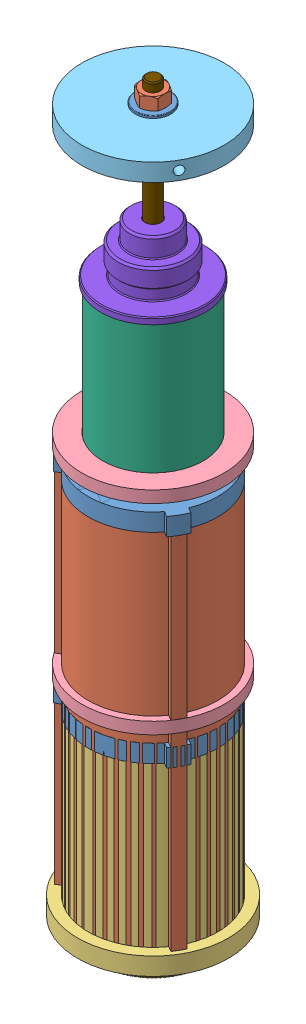
SolidWorks assembly S1B_Motor_Centering_Rings_Test, configuration Default. Lengths in mm.
Overall size (81.28 400.69 81.28).
31 component instances, 21 part files, 12 mates.
Components (placement in the parent):
- S1B_Motor_Casing_Centering_Ring_Jig_Top-1: S1B_Motor_Casing_Centering_Ring_Jig_Top [Default] at origin size (70.46 15.88 73.15) (hidden)
- S1B_Motor_Casing_Centering_Ring_Jig_Bottom-1: S1B_Motor_Casing_Centering_Ring_Jig_Bottom [Default] at (0 -193.675 0) size (69.85 193.68 73.15) (hidden)
- S1B_Propulsion-1: S1B_Propulsion [Default] at (0 -193.675 0) x (1 0 0) z (0 1 0) size (81.28 81.28 400.69)
  - S1B_Thrust_Block-1: S1B_Thrust_Block [Default] at (0 0 -9.525) x (1 0 0) z (0 1 0) size (81.28 9.53 81.28)
  - S1B_Motor_Casing_Centering_Ring-1: S1B_Motor_Casing_Centering_Ring [Default] at (0 0 209.55) x (0 1 0) z (-1 0 0) size (76.71 6.35 76.71)
  - S1B_Motor_Casing_Centering_Ring-2: S1B_Motor_Casing_Centering_Ring [Default] at (0 0 101.6) x (0 1 0) z (-1 0 0) size (76.71 6.35 76.71)
  - S1B_Propulsion_Forward_Bulkhead-1: S1B_Propulsion_Forward_Bulkhead [Default] at (0 0 359.3699) x (1 0 0) z (0 -1 0) size (76.71 9.53 76.71)
  - S1B_Motor_and_Motor_Casing-1: S1B_Motor_and_Motor_Casing [Default] at (-9.4594 -91.7964 22.8199) x (1 0 0) z (0 -1 0) size (79.29 334.89 79.29)
    - S1B_Casing-1: S1B_Casing [Default] at (9.4594 -32.3449 -91.7964) size (54 295.28 54)
    - S1B_Floating_Forward_Closure-1: S1B_Floating_Forward_Closure [Default] at (9.4594 165.0762 -91.7964) x (-0.998129 0 0.061137) z (-0.061137 0 -0.998129) size (50 49.2 50)
    - S1B_Forward_Closure-1: S1B_Forward_Closure [Default] at (9.4594 247.4801 -91.7964) x (0.980788 0 -0.195079) z (0.195079 0 0.980788) size (56.29 45.5 56.29)
    - S1B_Aft_Closure-2: S1B_Aft_Closure [Default] at (-1.9819 -17.8393 -106.5879) x (-0.611829 0 -0.79099) z (-0.79099 0 0.611829) size (56.53 20.87 56.51)
    - S1B_Aerospike_Nozzle-1: S1B_Aerospike_Nozzle [Default] at (9.4594 -15.9281 -91.7964) x (0.109916 0 -0.993941) z (-0.993941 0 -0.109916) size (50 32 50)
    - S1B_Aerospike_Nozzle_Ring-1: S1B_Aerospike_Nozzle_Ring [Default] at (9.4594 -26.9281 -91.7964) x (-0.620514 0 -0.784195) z (0.784195 0 -0.620514) size (44 9 44)
    - S1B_Grains-1: S1B_Grains [Default] at (9.4594 -7.6281 -91.7964) x (0.768519 0 0.639827) z (-0.639827 0 0.768519) size (47 82.35 47)
    - S1B_Grains-2: S1B_Grains [Default] at (9.4594 76.5219 -91.7964) x (-0.910958 0 0.412498) z (-0.412498 0 -0.910958) size (47 82.35 47)
    - S1B_Forward_Seal_Disk-1: S1B_Forward_Seal_Disk [Default] at (9.4594 165.0762 -91.7964) x (-0.490706 0 0.871325) z (0.871325 0 0.490706) size (50.4 6.2 50.4)
    - S1B_Case_Spacer-2: S1B_Case_Spacer [Default] at (9.4594 251.1262 -91.7964) x (0.880165 0 0.474668) z (0.474668 0 -0.880165) size (50.35 79.8 50.35)
    - S1B_9452K118_Oil-Resistant Buna-N O-Ring (031)-2: S1B_9452K118_Oil-Resistant Buna-N O-Ring (031) [9452K118] at (9.4594 75.6219 -91.7964) x (0.952073 0 -0.305872) z (0 -1 0) size (47.73 47.73 1.78)
    - S1B_9452K62_Oil-Resistant Buna-N O-Ring (224)-4: S1B_9452K62_Oil-Resistant Buna-N O-Ring (224) [9452K62] at (9.4594 -20.3449 -91.7964) x (0.99634 0 -0.085477) z (0 1 0) size (51.1 51.1 3.53)
    - S1B_9452K118_Oil-Resistant Buna-N O-Ring (031)-3: S1B_9452K118_Oil-Resistant Buna-N O-Ring (031) [9452K118] at (9.4594 160.3362 -91.7964) x (0.999977 0 -0.006714) z (0 1 0) size (47.73 47.73 1.78)
    - S1B_9452K62_Oil-Resistant Buna-N O-Ring (224)-5: S1B_9452K62_Oil-Resistant Buna-N O-Ring (224) [9452K62] at (9.4594 166.8762 -91.7964) x (0.97725 0 -0.21209) z (0 1 0) size (51.1 51.1 3.53)
    - S1B_9452K118_Oil-Resistant Buna-N O-Ring (031)-4: S1B_9452K118_Oil-Resistant Buna-N O-Ring (031) [9452K118] at (9.4594 -8.5281 -91.7964) x (0.924367 0 -0.381504) z (0 -1 0) size (47.73 47.73 1.78)
    - S1B_Liner-4: S1B_Liner [Default] at (9.4594 -15.9238 -91.7964) x (-0.821303 0 -0.570492) z (0.570492 0 -0.821303) size (50.7 177.66 50.7)
  - S1B_Propulsion_Threaded_Rod_90322A682_High-Strength Steel Threaded Rod-1: S1B_Propulsion_Threaded_Rod_90322A682_High-Strength Steel Threaded Rod [90322A682] at (0 0 330.7949) x (0 -1 0) z (0 0 1) size (7.94 7.94 101.6)
  - S1B_Propulsion_Threaded_Rod_90107A030_316 Stainless Steel Washer-1: S1B_Propulsion_Threaded_Rod_90107A030_316 Stainless Steel Washer [90107A030] at (0 0 369.5299) x (0 1 0) z (0 0 1) size (19.05 19.05 1.27)
  - S1B_Propulsion_Threaded_Rod_90107A030_316 Stainless Steel Washer-2: S1B_Propulsion_Threaded_Rod_90107A030_316 Stainless Steel Washer [90107A030] at (0 0 358.7349) size (19.05 19.05 1.27)
  - S1B_Propulsion_Threaded_Rod_95505A602_Medium-Strength Steel Hex Nut-1: S1B_Propulsion_Threaded_Rod_95505A602_Medium-Strength Steel Hex Nut [95505A602] at (0 0 373.5384) size (12.7 14.66 6.75)
  - S1B_Propulsion_Threaded_Rod_95505A602_Medium-Strength Steel Hex Nut-2: S1B_Propulsion_Threaded_Rod_95505A602_Medium-Strength Steel Hex Nut [95505A602] at (0 0 354.7265) size (12.7 14.66 6.75)
- S1B_Motor_Casing_Centering_Ring_Jig_Bottom_2-2: S1B_Motor_Casing_Centering_Ring_Jig_Bottom_2 [Default] at (0 -193.675 0) size (69.85 85.72 73.15)
- S1B_Motor_Casing_Centering_Ring_Jig_Top-2: S1B_Motor_Casing_Centering_Ring_Jig_Top [Default] at (0 -107.95 0) size (70.46 15.88 73.15)
Mates (geometry in assembly coordinates):
- Concentric1: concentric anti-aligned: cylinder of S1B_Motor_Casing_Centering_Ring_Jig_Top-1 through (0 0 0) axis (0 1 0) radius 5.08; cylinder of S1B_Motor_Casing_Centering_Ring_Jig_Bottom-1 through (0 0 0) axis (0 -1 0) radius 32.385
- Coincident1: coincident anti-aligned: plane of S1B_Motor_Casing_Centering_Ring_Jig_Top-1 through (0 0 0) normal (0 -1 0); plane of S1B_Motor_Casing_Centering_Ring_Jig_Bottom-1 through (0 0 0) normal (0 1 0)
- Parallel1: parallel aligned: plane of S1B_Motor_Casing_Centering_Ring_Jig_Top-1 through (0 0 0) normal (0 0 1); plane of S1B_Motor_Casing_Centering_Ring_Jig_Bottom-1 through (0 -193.675 0) normal (0 0 1)
- Coincident2: coincident anti-aligned: plane of S1B_Motor_Casing_Centering_Ring_Jig_Bottom-1 through (0 -193.675 0) normal (0 -1 0); plane of S1B_Propulsion-1/S1B_Thrust_Block-1 through (26.924 -193.675 0) normal (0 1 0)
- Parallel3: parallel anti-aligned: plane of S1B_Propulsion-1 through (0 -193.675 0) normal (0 0 -1)
- Concentric2: concentric anti-aligned: cylinder of S1B_Motor_Casing_Centering_Ring_Jig_Top-1 through (0 0 0) axis (0 1 0) radius 5.08; line of S1B_Propulsion-1 through (0 87.7443 0) axis (0 -1 0)
- Coincident3: coincident: plane of S1B_Motor_Casing_Centering_Ring_Jig_Bottom-1 through (0 -193.675 0) normal (0 -1 0); plane of S1B_Motor_Casing_Centering_Ring_Jig_Bottom_2-2 through (0 -193.675 0) normal (0 -1 0)
- Parallel4: parallel: plane of S1B_Motor_Casing_Centering_Ring_Jig_Top-1 through (0 0 0) normal (0 0 1); plane of S1B_Motor_Casing_Centering_Ring_Jig_Bottom_2-2 through (0 -193.675 0) normal (0 0 1)
- Concentric3: concentric anti-aligned: cylinder of S1B_Motor_Casing_Centering_Ring_Jig_Top-1 through (0 0 0) axis (0 1 0) radius 5.08; cylinder of S1B_Motor_Casing_Centering_Ring_Jig_Bottom_2-2 through (0 -107.95 0) axis (0 -1 0) radius 32.385
- Concentric4: concentric: cylinder of S1B_Motor_Casing_Centering_Ring_Jig_Bottom_2-2 through (0 -107.95 0) axis (0 -1 0) radius 32.385; cylinder of S1B_Motor_Casing_Centering_Ring_Jig_Top-2 through (0 -88.0394 0) axis (0 1 0) radius 5.08
- Parallel5: parallel: plane of S1B_Motor_Casing_Centering_Ring_Jig_Top-1 through (0 0 0) normal (0 0 1); plane of S1B_Motor_Casing_Centering_Ring_Jig_Top-2 through (0 -88.0394 0) normal (0 0 1)
- Coincident4: coincident anti-aligned: plane of S1B_Motor_Casing_Centering_Ring_Jig_Bottom_2-2 through (0 -107.95 0) normal (0 1 0); plane of S1B_Motor_Casing_Centering_Ring_Jig_Top-2 through (0 -88.0394 0) normal (0 -1 0)
